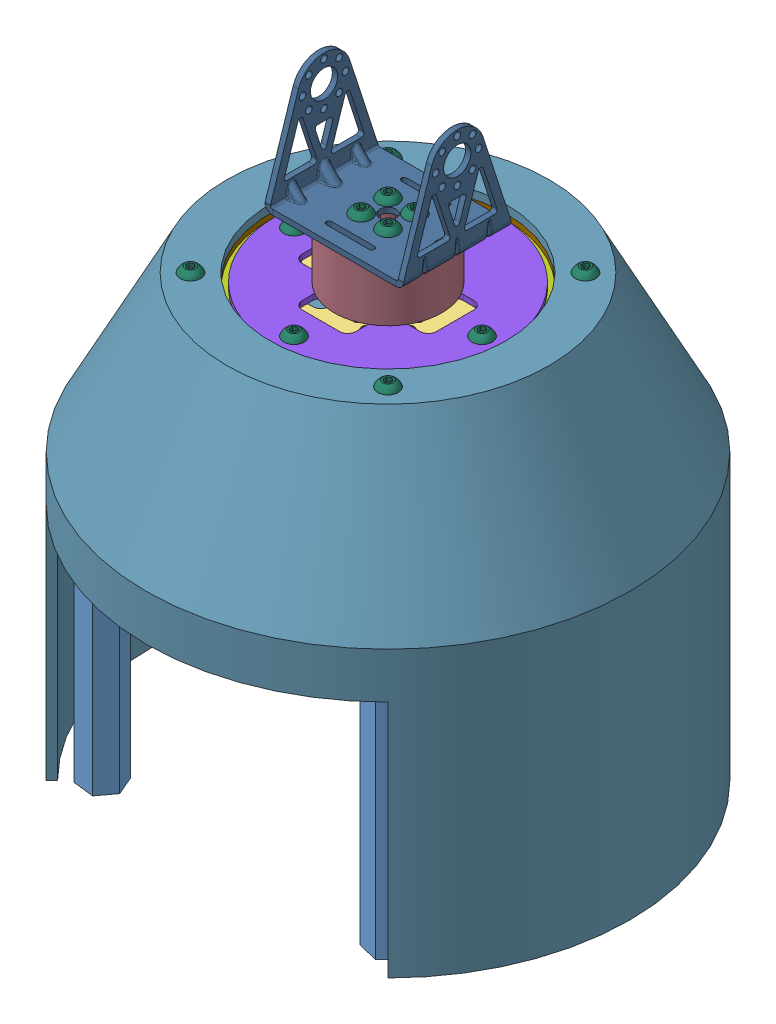
SolidWorks assembly 云台, configuration 默认. Lengths in mm.
Overall size (254.56 222.8 254.56).
45 component instances, 16 part files, 99 mates.
Components (placement in the parent):
- M8×100铜柱-1: M8×100铜柱 [默认] at (-53.9281 0 -53.9802) size (15.01 100 13)
- M8×100铜柱-2: M8×100铜柱 [默认] at (52.1379 0 -53.9802) size (15.01 100 13)
- M8×100铜柱-3: M8×100铜柱 [默认] at (53.6845 0 54.1617) x (-0.972827 0 -0.231533) z (0.231533 0 -0.972827) size (15.01 100 13)
- M8×100铜柱-4: M8×100铜柱 [默认] at (-52.5181 0 51.8358) x (0.396315 0 0.918115) z (-0.918115 0 0.396315) size (15.01 100 13)
- 6号舵机底座-1: 6号舵机底座 [默认] at (0 103 0) size (174 3 174)
- 轴承底座-1: 轴承底座 [默认] at (0 148.8 0) x (-1 0 0) z (0 0 -1) size (82 2 84)
- 舵机-1: 舵机 [默认] at (0 103 -9.65) x (0 0 1) z (-1 0 0) size (40 51.4 20)
- 主舵盘-1: 主舵盘 [默认] at (0 143.8 0) x (0 0 1) z (-1 0 0) size (20 5 20)
- 轴承外底座-1: 轴承外底座 [默认] at (0 148.8 0) x (0 0 1) z (-1 0 0) size (120 2 120)
- 轴承-1: 轴承 [默认] at (0 148.8 0) x (0.643268 0 0.765641) z (-0.765641 0 0.643268) size (100 10 100)
- 轴承顶-1: 轴承顶 [默认] at (0 160.8 0) x (-1 0 0) z (0 0 -1) size (84 2 84)
- 轴承外顶-1: 轴承外顶 [默认] at (0 160.8 0) x (-1 0 0) z (0 0 -1) size (120 2 120)
- 大U支架-1: 大U支架 [默认] at (0 182.8 0) x (-1 0 0) z (0 0 -1) size (51.6 42 40)
- 镙丝 PA2x12-半圆头十字(自攻)-6: 镙丝 PA2x12-半圆头十字(自攻) [默认] at (-8 150 0) x (-0.036972 0 -0.999316) z (0.999316 0 -0.036972) size (3.55 13.42 3.55)
- 镙丝 PA2x12-半圆头十字(自攻)-7: 镙丝 PA2x12-半圆头十字(自攻) [默认] at (-5.6569 150 -5.6569) x (0.629905 0 -0.776673) z (0.776673 0 0.629905) size (3.55 13.42 3.55)
- 镙丝 PA2x12-半圆头十字(自攻)-8: 镙丝 PA2x12-半圆头十字(自攻) [默认] at (0 150 -8) size (3.55 13.42 3.55)
- 镙丝 PA2x12-半圆头十字(自攻)-9: 镙丝 PA2x12-半圆头十字(自攻) [默认] at (5.6569 150 -5.6569) size (3.55 13.42 3.55)
- 镙丝 PA2x12-半圆头十字(自攻)-10: 镙丝 PA2x12-半圆头十字(自攻) [默认] at (8 150 0) size (3.55 13.42 3.55)
- 镙丝 PA2x12-半圆头十字(自攻)-11: 镙丝 PA2x12-半圆头十字(自攻) [默认] at (5.6569 150 5.6569) x (-0.275631 0 -0.961264) z (0.961264 0 -0.275631) size (3.55 13.42 3.55)
- 镙丝 PA2x12-半圆头十字(自攻)-12: 镙丝 PA2x12-半圆头十字(自攻) [默认] at (0 150 8) x (-0.36257 0 -0.931957) z (0.931957 0 -0.36257) size (3.55 13.42 3.55)
- 镙丝 PA2x12-半圆头十字(自攻)-13: 镙丝 PA2x12-半圆头十字(自攻) [默认] at (-5.6569 150 5.6569) x (-0.702759 0 -0.711428) z (0.711428 0 -0.702759) size (3.55 13.42 3.55)
- 镙丝 PA3x12-半圆头十字(自攻)-1: 镙丝 PA3x12-半圆头十字(自攻) [默认] at (0 150.8 0) size (5.3 14.31 5.3)
- 12号舵机连接管-1: 12号舵机连接管 [默认] at (0 160.8 0) x (0 0 1) z (-1 0 0) size (40 20 40)
- 云台外壳-1: 云台外壳 [默认] at (0 160.8 0) x (0.707107 0 0.707107) z (-0.707107 0 0.707107) size (180 163.8 180)
- hexagon socket button head screws gb-34: hexagon socket button head screws gb [GB_SOCKET_TYPE7 M4X16-N] at (35 163 0) x (0 -1 0) z (0 0 1) size (18.2 7.6 7.6)
- hexagon socket button head screws gb-35: hexagon socket button head screws gb [GB_SOCKET_TYPE7 M4X16-N] at (0 163 -35) x (0 -1 0) z (0 0 1) size (18.2 7.6 7.6)
- hexagon socket button head screws gb-36: hexagon socket button head screws gb [GB_SOCKET_TYPE7 M4X16-N] at (0 163 35) x (0 -1 0) z (0 0 1) size (18.2 7.6 7.6)
- hexagon socket button head screws gb-37: hexagon socket button head screws gb [GB_SOCKET_TYPE7 M4X16-N] at (-35 163 0) x (0 -1 0) z (0 0 1) size (18.2 7.6 7.6)
- hexagon socket button head screws gb-38: hexagon socket button head screws gb [GB_SOCKET_TYPE7 M4X16-N] at (36.7696 166 36.7696) x (0 -1 0) z (0 0 1) size (18.2 7.6 7.6)
- hexagon socket button head screws gb-39: hexagon socket button head screws gb [GB_SOCKET_TYPE7 M4X16-N] at (36.7696 166 -36.7696) x (0 -1 0) z (0 0 1) size (18.2 7.6 7.6)
- hexagon socket button head screws gb-40: hexagon socket button head screws gb [GB_SOCKET_TYPE7 M4X16-N] at (-36.7696 166 -36.7696) x (0 -1 0) z (0 0 1) size (18.2 7.6 7.6)
- hexagon socket button head screws gb-41: hexagon socket button head screws gb [GB_SOCKET_TYPE7 M4X16-N] at (-36.7696 166 36.7696) x (0 -1 0) z (0 0 1) size (18.2 7.6 7.6)
- hexagon socket button head screws gb-42: hexagon socket button head screws gb [GB_SOCKET_TYPE7 M4X16-N] at (5 185 5) x (0 -1 0) z (0 0 1) size (18.2 7.6 7.6)
- hexagon socket button head screws gb-43: hexagon socket button head screws gb [GB_SOCKET_TYPE7 M4X16-N] at (5 185 -5) x (0 -1 0) z (0 0 1) size (18.2 7.6 7.6)
- hexagon socket button head screws gb-44: hexagon socket button head screws gb [GB_SOCKET_TYPE7 M4X16-N] at (-5 185 5) x (0 -1 0) z (0 0 1) size (18.2 7.6 7.6)
- hexagon socket button head screws gb-45: hexagon socket button head screws gb [GB_SOCKET_TYPE7 M4X16-N] at (-5 185 -5) x (0 -1 0) z (0 0 1) size (18.2 7.6 7.6)
- hexagon socket button head screws gb-47: hexagon socket button head screws gb [GB_SOCKET_TYPE7 M8X40-N] at (-53.033 110.4 -53.033) x (0 -1 0) z (0 0 1) size (44.4 14 14)
- hexagon socket button head screws gb-48: hexagon socket button head screws gb [GB_SOCKET_TYPE7 M8X40-N] at (53.033 110.4 -53.033) x (0 -1 0) z (0 0 1) size (44.4 14 14)
- hexagon socket button head screws gb-49: hexagon socket button head screws gb [GB_SOCKET_TYPE7 M8X40-N] at (53.033 110.4 53.033) x (0 -1 0) z (0 0 1) size (44.4 14 14)
- hexagon socket button head screws gb-50: hexagon socket button head screws gb [GB_SOCKET_TYPE7 M8X40-N] at (-53.033 110.4 53.033) x (0 -1 0) z (0 0 1) size (44.4 14 14)
- 镙丝 PM2x8-半圆头-1: 镙丝 PM2x8-半圆头 [默认] at (-8 98.8 -9.15) x (0.837169 0 0.546944) z (0.546944 0 -0.837169) size (3.55 9.32 3.55)
- 镙丝 PM2x8-半圆头-2: 镙丝 PM2x8-半圆头 [默认] at (-7 98.8 -20.15) x (0.837169 0 0.546944) z (0.546944 0 -0.837169) size (3.55 9.32 3.55)
- 镙丝 PM2x8-半圆头-3: 镙丝 PM2x8-半圆头 [默认] at (8 98.8 -9.15) x (0.837169 0 0.546944) z (0.546944 0 -0.837169) size (3.55 9.32 3.55)
- 镙丝 PM2x8-半圆头-4: 镙丝 PM2x8-半圆头 [默认] at (7 98.8 -20.15) x (0.837169 0 0.546944) z (0.546944 0 -0.837169) size (3.55 9.32 3.55)
- 镙丝 PM2x8-半圆头-5: 镙丝 PM2x8-半圆头 [默认] at (0 98.8 -27.15) x (0.837169 0 0.546944) z (0.546944 0 -0.837169) size (3.55 9.32 3.55)
Mates (geometry in assembly coordinates):
- 重合5: coincident anti-aligned: plane of M8×100铜柱-3 through (53.6845 100 54.1617) normal (0 1 0); plane of 6号舵机底座-1 through (0 100 0) normal (0 -1 0)
- 同心5: concentric aligned: circle of M8×100铜柱-3; circle of 6号舵机底座-1
- 同心6: concentric aligned: circle of M8×100铜柱-4; circle of 6号舵机底座-1
- 同心12: concentric aligned: circle of 6号舵机底座-1; circle of 轴承底座-1
- 重合13: coincident anti-aligned: plane of 舵机-1 through (0 143.8 0) normal (0 1 0); plane of 主舵盘-1 through (0 143.8 0) normal (0 -1 0)
- 同心13: concentric anti-aligned: circle of 舵机-1; circle of 主舵盘-1
- 同心14: concentric aligned: circle of 轴承底座-1; circle of 主舵盘-1
- 平行2: parallel anti-aligned: line of 6号舵机底座-1 through (-30 103 7) axis (0 0 -1); line of 舵机-1 through (-10 103.5 -25.15) axis (0 0 1)
- 重合15: coincident anti-aligned: plane of 轴承底座-1 through (0 146.8 0) normal (0 -1 0); plane of 主舵盘-1 through (0 146.8 0) normal (0 1 0)
- 同心21: concentric aligned: circle of 轴承底座-1; circle of 轴承外底座-1
- 重合22: coincident anti-aligned: plane of 轴承外底座-1 through (0 148.8 0) normal (0 1 0); plane of 轴承-1 through (0 148.8 0) normal (0 -1 0)
- 同心22: concentric aligned: circle of 轴承外底座-1; circle of 轴承-1
- 同心24: concentric aligned: circle of 轴承底座-1; circle of 主舵盘-1
- 重合23: coincident anti-aligned: plane of 轴承-1 through (0 158.8 0) normal (0 1 0); plane of 轴承顶-1 through (0 158.8 0) normal (0 -1 0)
- 同心25: concentric aligned: circle of 轴承底座-1; circle of 轴承顶-1
- 平行3: parallel anti-aligned: line of 轴承底座-1 through (-15 146.8 -7) axis (0 0 1); line of 轴承顶-1 through (-15 160.8 7) axis (0 0 -1)
- 重合25: coincident anti-aligned: plane of 轴承-1 through (0 158.8 0) normal (0 1 0); plane of 轴承外顶-1 through (0 158.8 0) normal (0 -1 0)
- 同心26: concentric aligned: circle of 轴承-1; circle of 轴承外顶-1
- 同心27: concentric aligned: circle of 轴承外底座-1; circle of 轴承外顶-1
- 同心68: concentric aligned: circle of 轴承底座-1; circle of 镙丝 PA2x12-半圆头十字(自攻)-6
- 同心69: concentric aligned: circle of 轴承底座-1; circle of 镙丝 PA2x12-半圆头十字(自攻)-7
- 同心70: concentric aligned: circle of 轴承底座-1; circle of 镙丝 PA2x12-半圆头十字(自攻)-8
- 同心71: concentric aligned: circle of 轴承底座-1; circle of 镙丝 PA2x12-半圆头十字(自攻)-9
- 同心72: concentric aligned: circle of 轴承底座-1; circle of 镙丝 PA2x12-半圆头十字(自攻)-10
- 同心73: concentric aligned: circle of 轴承底座-1; circle of 镙丝 PA2x12-半圆头十字(自攻)-13
- 同心74: concentric aligned: circle of 轴承底座-1; circle of 镙丝 PA2x12-半圆头十字(自攻)-12
- 同心75: concentric aligned: circle of 轴承底座-1; circle of 镙丝 PA2x12-半圆头十字(自攻)-11
- 重合71: coincident anti-aligned: plane of 轴承底座-1 through (0 148.8 0) normal (0 1 0); plane of 镙丝 PA2x12-半圆头十字(自攻)-10 through (8 148.8 -11.3916) normal (0 -1 0)
- 重合72: coincident anti-aligned: plane of 轴承底座-1 through (0 148.8 0) normal (0 1 0); plane of 镙丝 PA2x12-半圆头十字(自攻)-9 through (5.6569 148.8 -17.0485) normal (0 -1 0)
- 重合73: coincident anti-aligned: plane of 轴承底座-1 through (0 148.8 0) normal (0 1 0); plane of 镙丝 PA2x12-半圆头十字(自攻)-8 through (0 148.8 -19.3916) normal (0 -1 0)
- 重合74: coincident anti-aligned: plane of 轴承底座-1 through (0 148.8 0) normal (0 1 0); plane of 镙丝 PA2x12-半圆头十字(自攻)-11 through (-5.2935 148.8 8.7967) normal (0 -1 0)
- 重合75: coincident anti-aligned: plane of 轴承底座-1 through (0 148.8 0) normal (0 1 0); plane of 镙丝 PA2x12-半圆头十字(自攻)-12 through (-10.6165 148.8 12.1303) normal (0 -1 0)
- 重合76: coincident anti-aligned: plane of 轴承底座-1 through (0 148.8 0) normal (0 1 0); plane of 镙丝 PA2x12-半圆头十字(自攻)-13 through (-13.7612 148.8 13.6624) normal (0 -1 0)
- 重合77: coincident anti-aligned: plane of 轴承底座-1 through (0 148.8 0) normal (0 1 0); plane of 镙丝 PA2x12-半圆头十字(自攻)-6 through (-19.3838 148.8 0.4212) normal (0 -1 0)
- 重合78: coincident anti-aligned: plane of 轴承底座-1 through (0 148.8 0) normal (0 1 0); plane of 镙丝 PA2x12-半圆头十字(自攻)-7 through (-14.5044 148.8 -12.8325) normal (0 -1 0)
- 同心76: concentric anti-aligned: circle of 主舵盘-1; circle of 镙丝 PA3x12-半圆头十字(自攻)-1
- 重合79: coincident anti-aligned: plane of 轴承底座-1 through (0 148.8 0) normal (0 1 0); plane of 镙丝 PA3x12-半圆头十字(自攻)-1 through (0 148.8 0) normal (0 -1 0)
- 同心77: concentric aligned: circle of 轴承顶-1; circle of 12号舵机连接管-1
- 同心78: concentric aligned: circle of 轴承顶-1; circle of 12号舵机连接管-1
- 重合82: coincident anti-aligned: plane of 轴承顶-1 through (0 160.8 0) normal (0 1 0); plane of 12号舵机连接管-1 through (0 160.8 0) normal (0 -1 0)
- 同心79: concentric anti-aligned: circle of 大U支架-1; circle of 12号舵机连接管-1
- 同心80: concentric anti-aligned: circle of 大U支架-1; circle of 12号舵机连接管-1
- 重合85: coincident anti-aligned: plane of 大U支架-1 through (0 180.8 0) normal (0 -1 0); plane of 12号舵机连接管-1 through (0 180.8 0) normal (0 1 0)
- 同心81: concentric aligned: circle of 轴承外底座-1; circle of 轴承外顶-1
- 重合87: coincident anti-aligned: plane of M8×100铜柱-1 through (-53.9281 100 -53.9802) normal (0 1 0); plane of 6号舵机底座-1 through (0 100 0) normal (0 -1 0)
- 同心90: concentric aligned: circle of M8×100铜柱-1; circle of 6号舵机底座-1
- 同心91: concentric aligned: circle of M8×100铜柱-2; circle of 6号舵机底座-1
- 重合88: coincident anti-aligned: plane of M8×100铜柱-2 through (52.1379 100 -53.9802) normal (0 1 0); plane of 6号舵机底座-1 through (0 100 0) normal (0 -1 0)
- 重合89: coincident anti-aligned: plane of M8×100铜柱-4 through (-52.5181 100 51.8358) normal (0 1 0); plane of 6号舵机底座-1 through (0 100 0) normal (0 -1 0)
- 重合91: coincident anti-aligned: plane of 轴承底座-1 through (0 148.8 0) normal (0 1 0); plane of 轴承-1 through (0 148.8 0) normal (0 -1 0)
- 重合92: coincident anti-aligned: plane of 6号舵机底座-1 through (0 103 0) normal (0 1 0); plane of 舵机-1 through (0 103 -9.65) normal (0 -1 0)
- 同心94: concentric aligned: circle of 轴承外顶-1; circle of 云台外壳-1
- 同心99: concentric aligned: cylinder of 轴承顶-1 through (35 158.799 0) axis (0 1 0) radius 2.1; cylinder of hexagon socket button head screws gb-34 through (35 144.8 0) axis (0 1 0) radius 2
- 重合101: coincident anti-aligned: plane of 轴承顶-1 through (0 160.8 0) normal (0 1 0); plane of hexagon socket button head screws gb-34 through (35 160.8 0) normal (0 -1 0)
- 同心100: concentric aligned: cylinder of 轴承顶-1 through (0 158.799 -35) axis (0 1 0) radius 2.1; cylinder of hexagon socket button head screws gb-35 through (0 144.8 -35) axis (0 1 0) radius 2
- 重合102: coincident anti-aligned: plane of 轴承顶-1 through (0 160.8 0) normal (0 1 0); plane of hexagon socket button head screws gb-35 through (0 160.8 -35) normal (0 -1 0)
- 同心101: concentric aligned: cylinder of 轴承顶-1 through (0 158.799 35) axis (0 1 0) radius 2.1; cylinder of hexagon socket button head screws gb-36 through (0 144.8 35) axis (0 1 0) radius 2
- 重合103: coincident anti-aligned: plane of 轴承顶-1 through (0 160.8 0) normal (0 1 0); plane of hexagon socket button head screws gb-36 through (0 160.8 35) normal (0 -1 0)
- 同心102: concentric aligned: cylinder of 轴承顶-1 through (-35 158.799 0) axis (0 1 0) radius 2.1; cylinder of hexagon socket button head screws gb-37 through (-35 144.8 0) axis (0 1 0) radius 2
- 重合104: coincident anti-aligned: plane of 轴承顶-1 through (0 160.8 0) normal (0 1 0); plane of hexagon socket button head screws gb-37 through (-35 160.8 0) normal (0 -1 0)
- 重合105: coincident anti-aligned: plane of 轴承外顶-1 through (0 160.8 0) normal (0 1 0); plane of 云台外壳-1 through (0 160.8 0) normal (0 -1 0)
- 同心103: concentric anti-aligned: cylinder of 云台外壳-1 through (36.7696 163.8 36.7696) axis (0 -1 0) radius 2.1; cylinder of hexagon socket button head screws gb-38 through (36.7696 147.8 36.7696) axis (0 1 0) radius 2
- 重合106: coincident anti-aligned: plane of 云台外壳-1 through (0 163.8 0) normal (0 1 0); plane of hexagon socket button head screws gb-38 through (36.7696 163.8 36.7696) normal (0 -1 0)
- 同心104: concentric anti-aligned: cylinder of 云台外壳-1 through (36.7696 163.8 -36.7696) axis (0 -1 0) radius 2.1; cylinder of hexagon socket button head screws gb-39 through (36.7696 147.8 -36.7696) axis (0 1 0) radius 2
- 重合107: coincident anti-aligned: plane of 云台外壳-1 through (0 163.8 0) normal (0 1 0); plane of hexagon socket button head screws gb-39 through (36.7696 163.8 -36.7696) normal (0 -1 0)
- 同心105: concentric anti-aligned: cylinder of 云台外壳-1 through (-36.7696 163.8 -36.7696) axis (0 -1 0) radius 2.1; cylinder of hexagon socket button head screws gb-40 through (-36.7696 147.8 -36.7696) axis (0 1 0) radius 2
- 重合108: coincident anti-aligned: plane of 云台外壳-1 through (0 163.8 0) normal (0 1 0); plane of hexagon socket button head screws gb-40 through (-36.7696 163.8 -36.7696) normal (0 -1 0)
- 同心106: concentric anti-aligned: cylinder of 云台外壳-1 through (-36.7696 163.8 36.7696) axis (0 -1 0) radius 2.1; cylinder of hexagon socket button head screws gb-41 through (-36.7696 147.8 36.7696) axis (0 1 0) radius 2
- 重合109: coincident anti-aligned: plane of 云台外壳-1 through (0 163.8 0) normal (0 1 0); plane of hexagon socket button head screws gb-41 through (-36.7696 163.8 36.7696) normal (0 -1 0)
- 同心107: concentric anti-aligned: cylinder of 大U支架-1 through (5 222.801 5) axis (0 -1 0) radius 2; cylinder of hexagon socket button head screws gb-42 through (5 166.8 5) axis (0 1 0) radius 2
- 重合110: coincident anti-aligned: plane of 大U支架-1 through (0 182.8 0) normal (0 1 0); plane of hexagon socket button head screws gb-42 through (5 182.8 5) normal (0 -1 0)
- 同心108: concentric anti-aligned: cylinder of 大U支架-1 through (5 222.801 -5) axis (0 -1 0) radius 2; cylinder of hexagon socket button head screws gb-43 through (5 166.8 -5) axis (0 1 0) radius 2
- 重合111: coincident anti-aligned: plane of 大U支架-1 through (0 182.8 0) normal (0 1 0); plane of hexagon socket button head screws gb-43 through (5 182.8 -5) normal (0 -1 0)
- 同心109: concentric anti-aligned: cylinder of 大U支架-1 through (-5 222.801 5) axis (0 -1 0) radius 2; cylinder of hexagon socket button head screws gb-44 through (-5 166.8 5) axis (0 1 0) radius 2
- 重合112: coincident anti-aligned: plane of 大U支架-1 through (0 182.8 0) normal (0 1 0); plane of hexagon socket button head screws gb-44 through (-5 182.8 5) normal (0 -1 0)
- 同心110: concentric anti-aligned: cylinder of 大U支架-1 through (-5 222.801 -5) axis (0 -1 0) radius 2; cylinder of hexagon socket button head screws gb-45 through (-5 166.8 -5) axis (0 1 0) radius 2
- 重合113: coincident anti-aligned: plane of 大U支架-1 through (0 182.8 0) normal (0 1 0); plane of hexagon socket button head screws gb-45 through (-5 182.8 -5) normal (0 -1 0)
- 同心115: concentric anti-aligned: circle of 6号舵机底座-1; circle of 云台外壳-1
- 同心116: concentric aligned: circle of 6号舵机底座-1; circle of 云台外壳-1
- 同心117: concentric aligned: cylinder of 云台外壳-1 through (-53.033 103 -53.033) axis (0 1 0) radius 4.1; cylinder of hexagon socket button head screws gb-47 through (-53.033 66 -53.033) axis (0 1 0) radius 4
- 重合116: coincident anti-aligned: plane of 云台外壳-1 through (0 106 0) normal (0 1 0); plane of hexagon socket button head screws gb-47 through (-53.033 106 -53.033) normal (0 -1 0)
- 同心118: concentric aligned: cylinder of 云台外壳-1 through (53.033 103 -53.033) axis (0 1 0) radius 4.1; cylinder of hexagon socket button head screws gb-48 through (53.033 66 -53.033) axis (0 1 0) radius 4
- 重合117: coincident anti-aligned: plane of 云台外壳-1 through (0 106 0) normal (0 1 0); plane of hexagon socket button head screws gb-48 through (53.033 106 -53.033) normal (0 -1 0)
- 同心119: concentric aligned: cylinder of 云台外壳-1 through (53.033 103 53.033) axis (0 1 0) radius 4.1; cylinder of hexagon socket button head screws gb-49 through (53.033 66 53.033) axis (0 1 0) radius 4
- 重合118: coincident anti-aligned: plane of 云台外壳-1 through (0 106 0) normal (0 1 0); plane of hexagon socket button head screws gb-49 through (53.033 106 53.033) normal (0 -1 0)
- 同心120: concentric aligned: cylinder of 云台外壳-1 through (-53.033 103 53.033) axis (0 1 0) radius 4.1; cylinder of hexagon socket button head screws gb-50 through (-53.033 66 53.033) axis (0 1 0) radius 4
- 重合119: coincident anti-aligned: plane of 云台外壳-1 through (0 106 0) normal (0 1 0); plane of hexagon socket button head screws gb-50 through (-53.033 106 53.033) normal (0 -1 0)
- 同心121: concentric aligned: circle of 6号舵机底座-1; circle of 镙丝 PM2x8-半圆头-1
- 重合120: coincident anti-aligned: plane of 6号舵机底座-1 through (0 100 0) normal (0 -1 0); plane of 镙丝 PM2x8-半圆头-1 through (-12.5505 100 -2.1849) normal (0 1 0)
- 同心122: concentric aligned: circle of 6号舵机底座-1; circle of 镙丝 PM2x8-半圆头-2
- 重合121: coincident anti-aligned: plane of 6号舵机底座-1 through (0 100 0) normal (0 -1 0); plane of 镙丝 PM2x8-半圆头-2 through (-11.5505 100 -13.1849) normal (0 1 0)
- 同心123: concentric aligned: circle of 6号舵机底座-1; circle of 镙丝 PM2x8-半圆头-5
- 重合122: coincident anti-aligned: plane of 6号舵机底座-1 through (0 100 0) normal (0 -1 0); plane of 镙丝 PM2x8-半圆头-5 through (-4.5505 100 -20.1849) normal (0 1 0)
- 同心124: concentric aligned: circle of 6号舵机底座-1; circle of 镙丝 PM2x8-半圆头-4
- 重合123: coincident anti-aligned: plane of 6号舵机底座-1 through (0 100 0) normal (0 -1 0); plane of 镙丝 PM2x8-半圆头-4 through (2.4495 100 -13.1849) normal (0 1 0)
- 同心125: concentric aligned: circle of 6号舵机底座-1; circle of 镙丝 PM2x8-半圆头-3
- 重合124: coincident anti-aligned: plane of 6号舵机底座-1 through (0 100 0) normal (0 -1 0); plane of 镙丝 PM2x8-半圆头-3 through (3.4495 100 -2.1849) normal (0 1 0)
- 平行4: parallel anti-aligned: plane of 6号舵机底座-1 through (0 103 0) normal (1 0 0); plane of 轴承顶-1 through (0 160.8 0) normal (-1 0 0)
- 重合126: coincident: plane of M8×100铜柱-4 through (-52.5181 0 51.8358) normal (0 -1 0)
